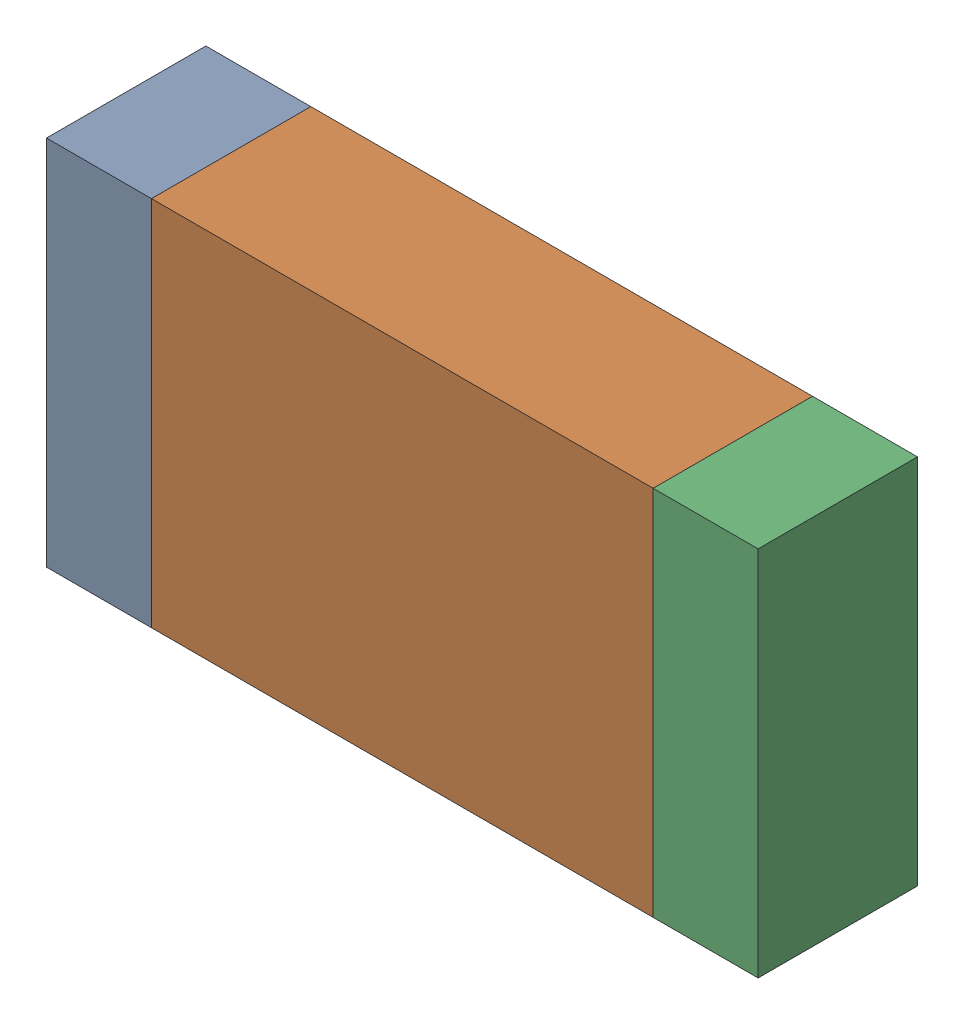
SolidWorks assembly R03, configuration Default. Lengths in mm.
Overall size (3.35 1.75 0.75).
6 component instances, 2 part files, 0 mates.
Components (placement in the parent):
- 959206760-1: 959206760 [Default] at (147.8506 77.6516 0) size (0.49 1.75 0.75)
  - Extruded-2-1: Extruded-2 [Default] at origin size (0.49 1.75 0.75)
- 959206896-1: 959206896 [Default] at (149.2781 77.6516 0) size (2.36 1.75 0.75)
  - Extruded-3-1: Extruded-3 [Default] at origin size (2.36 1.75 0.75)
- 959206760-2: 959206760 [Default] at (150.7056 77.6516 0) size (0.49 1.75 0.75)
  - Extruded-2-1: Extruded-2 [Default] at origin size (0.49 1.75 0.75)
